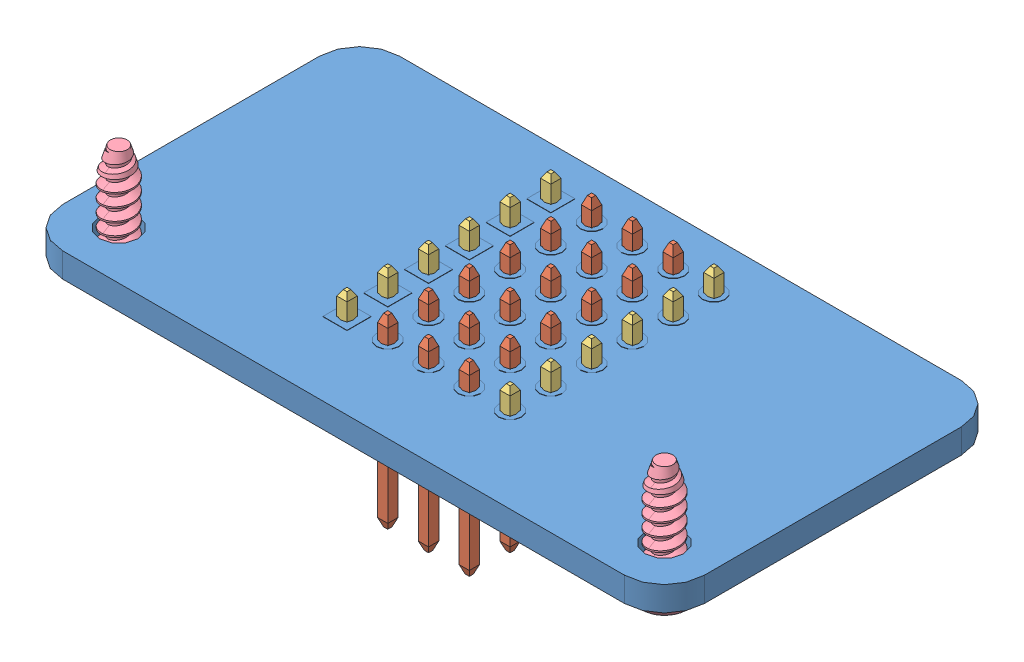
SolidWorks assembly i2C_Breakout_ASSY, configuration Default. Lengths in mm.
Overall size (40 14.54 21).
8 component instances, 4 part files, 25 mates.
Components (placement in the parent):
- circuitBoardi2c v1-1: circuitBoardi2c v1 [6x5] x (1 0 0) z (0 0 -1) size (40 1.6 21)
- pinHeader-2: pinHeader [6 pin] at (3.81 -1.53 3.93) x (0 0 1) z (1 0 0) size (15.24 11.54 2.54)
- pinHeader-3: pinHeader [6 pin] at (1.27 -1.53 3.93) x (0 0 1) z (1 0 0) size (15.24 11.54 2.54)
- pinHeader-4: pinHeader [6 pin] at (-1.27 -1.53 3.93) x (0 0 1) z (1 0 0) size (15.24 11.54 2.54)
- pinHeaderBend-1: pinHeaderBend [6 pin] at (-5.08 -1.53 5.2) x (0 0 1) z (1 0 0) size (15.24 7.32 8.52)
- pinHeaderBend-2: pinHeaderBend [6 pin] at (5.08 -1.53 -7.5) x (0 0 -1) z (-1 0 0) size (15.24 7.32 8.52)
- screw_m2.5_course-1: screw_m2.5_course [96817A209] at (-17 -1.53 7.5) x (-1 0 0) z (0 -1 0) size (3.35 3.35 7.64)
- screw_m2.5_course-2: screw_m2.5_course [96817A209] at (17 -1.53 7.5) x (-1 0 0) z (0 -1 0) size (3.35 3.35 7.64)
Mates (geometry in assembly coordinates):
- Coincident9: coincident aligned: plane of circuitBoardi2c v1-1 through (0 0 0) normal (1 0 0)
- Coincident14: coincident anti-aligned: plane of circuitBoardi2c v1-1 through (0 -1.53 0) normal (0 -1 0); plane of pinHeader-2 through (3.81 -1.53 3.93) normal (0 1 0)
- Concentric2: concentric anti-aligned: cylinder of circuitBoardi2c v1-1 through (2.54 2.0199 5.2) axis (0 -1 0) radius 0.39; line of pinHeader-2 through (2.54 -4.07 5.2) axis (0 1 0)
- Parallel2: parallel aligned: plane of circuitBoardi2c v1-1 through (-20 -1.53 10.5) normal (0 0 1); plane of pinHeader-2 through (3.81 -4.07 6.47) normal (0 0 1)
- Coincident15: coincident anti-aligned: plane of circuitBoardi2c v1-1 through (0 -1.53 0) normal (0 -1 0); plane of pinHeader-3 through (1.27 -1.53 3.93) normal (0 1 0)
- Parallel3: parallel aligned: plane of circuitBoardi2c v1-1 through (-20 -1.53 10.5) normal (0 0 1); plane of pinHeader-3 through (1.27 -4.07 6.47) normal (0 0 1)
- Concentric3: concentric anti-aligned: cylinder of circuitBoardi2c v1-1 through (0 2.0199 5.2) axis (0 -1 0) radius 0.39; line of pinHeader-3 through (0 -4.07 5.2) axis (0 1 0)
- Coincident16: coincident anti-aligned: plane of circuitBoardi2c v1-1 through (0 -1.53 0) normal (0 -1 0); plane of pinHeader-4 through (-1.27 -1.53 3.93) normal (0 1 0)
- Parallel4: parallel aligned: plane of circuitBoardi2c v1-1 through (-20 -1.53 10.5) normal (0 0 1); plane of pinHeader-4 through (-1.27 -4.07 6.47) normal (0 0 1)
- Concentric4: concentric anti-aligned: cylinder of circuitBoardi2c v1-1 through (-2.54 2.0199 5.2) axis (0 -1 0) radius 0.39; line of pinHeader-4 through (-2.54 -4.07 5.2) axis (0 1 0)
- Coincident18: coincident anti-aligned: plane of circuitBoardi2c v1-1 through (0 0 0) normal (0 0 -1)
- Coincident19: coincident anti-aligned: plane of circuitBoardi2c v1-1 through (0 0 0) normal (0 -1 0)
- Coincident20: coincident aligned: plane of circuitBoardi2c v1-1 through (0 0 0) normal (1 0 0)
- Concentric6: concentric aligned: cylinder of circuitBoardi2c v1-1 through (-17 0 7.5) axis (0 -1 0) radius 1.2; line of screw M2 plastic-1 through (-17 -5.7077 7.5) axis (0 -1 0)
- Coincident22: coincident anti-aligned: plane of circuitBoardi2c v1-1 through (0 -1.53 0) normal (0 -1 0); plane of screw M2 plastic-1 through (-17 -1.53 7.5) normal (0 1 0)
- Concentric7: concentric aligned: cylinder of circuitBoardi2c v1-1 through (17 0 7.5) axis (0 -1 0) radius 1.2; line of screw M2 plastic-2 through (17 -5.7077 7.5) axis (0 -1 0)
- Coincident23: coincident anti-aligned: plane of circuitBoardi2c v1-1 through (0 -1.53 0) normal (0 -1 0); plane of screw M2 plastic-2 through (17 -1.53 7.5) normal (0 1 0)
- Parallel6: parallel anti-aligned: plane of screw M2 plastic-1 through (-17 -1.53 7.5) normal (-1 0 0)
- Parallel7: parallel anti-aligned: plane of screw M2 plastic-2 through (17 -1.53 7.5) normal (-1 0 0)
- Concentric8: concentric aligned: line of pinHeaderBend-1 through (-5.08 -1.403 5.2) axis (0 -1 0); cylinder of circuitBoardi2c v1-1 through (-5.08 2.1613 5.2) axis (0 -1 0) radius 0.39
- Coincident24: coincident aligned: plane of circuitBoardi2c v1-1 through (0 -1.53 0) normal (0 -1 0); plane of pinHeaderBend-1 through (-5.08 -1.53 5.2) normal (0 -1 0)
- Parallel8: parallel aligned: plane of pinHeaderBend-1 through (-5.08 -1.53 5.2) normal (1 0 0)
- Concentric9: concentric aligned: cylinder of circuitBoardi2c v1-1 through (5.08 2.0199 -7.5) axis (0 -1 0) radius 0.39; line of pinHeaderBend-2 through (5.08 -1.403 -7.5) axis (0 -1 0)
- Coincident26: coincident aligned: plane of circuitBoardi2c v1-1 through (0 -1.53 0) normal (0 -1 0); plane of pinHeaderBend-2 through (5.08 -1.53 -7.5) normal (0 -1 0)
- Parallel10: parallel anti-aligned: plane of pinHeaderBend-2 through (5.08 -1.53 -7.5) normal (-1 0 0)
